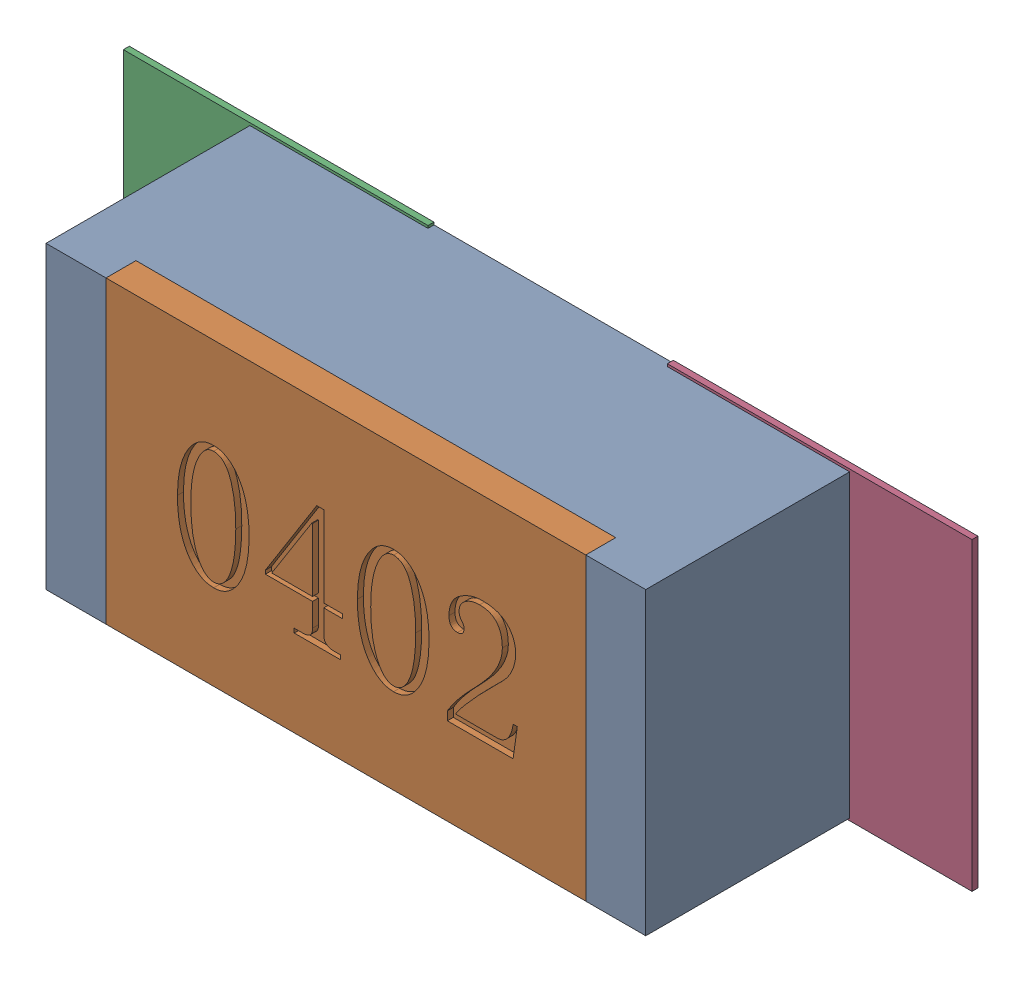
SolidWorks assembly R74, configuration Défaut. Lengths in mm.
Overall size (1.42 0.51 0.35).
5 component instances, 2 part files, 0 mates.
Components (placement in the parent):
- R0402-1: R0402 [Défaut] at (32.1914 -13.9479 0) x (1 0 0) z (0 0 1) size (1 0.5 0.35)
- 6504207776-1: 6504207776 [Défaut] at (31.7343 -13.9478 0) size (0.51 0.51 0.01)
  - Extruded-1: Extruded [Défaut] at origin size (0.51 0.51 0.01)
- 6504207776-2: 6504207776 [Défaut] at (32.6414 -13.9478 0) size (0.51 0.51 0.01)
  - Extruded-1: Extruded [Défaut] at origin size (0.51 0.51 0.01)
